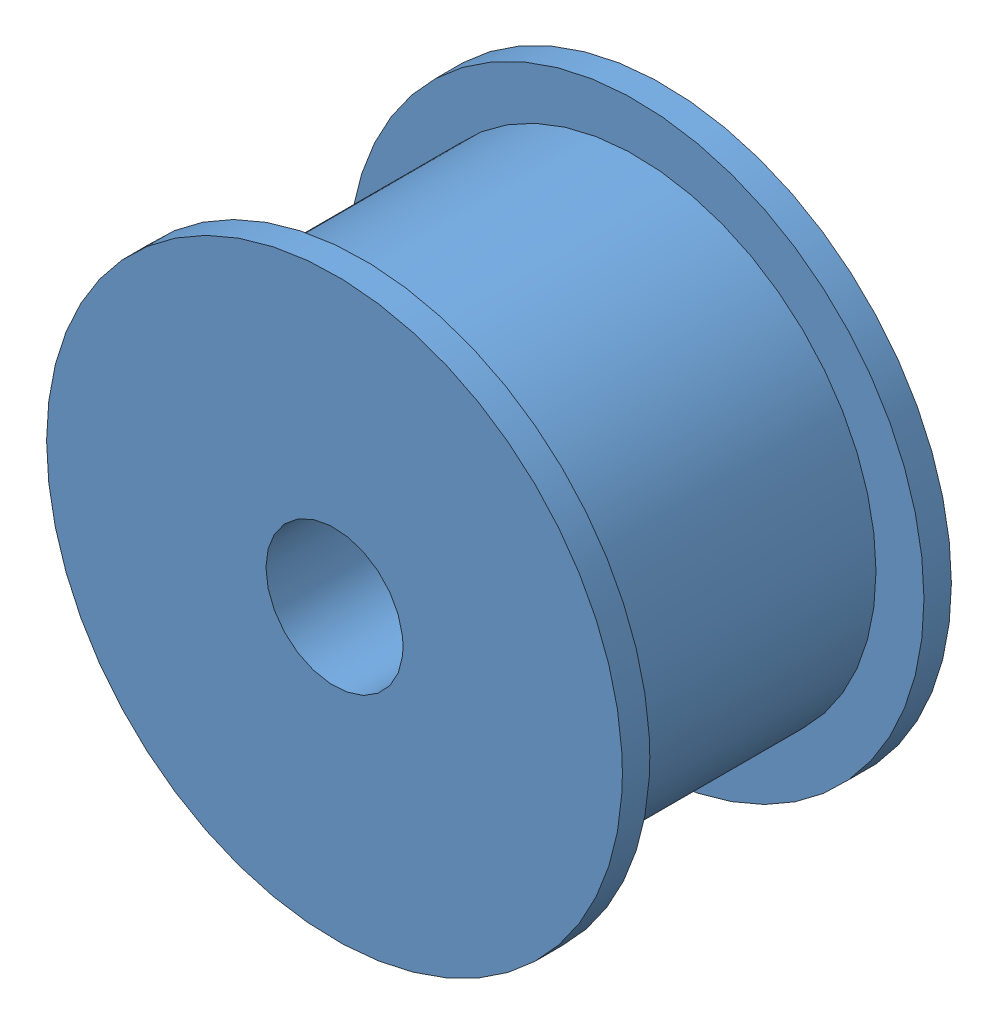
SolidWorks assembly Assemblage Poulie Lisse BRS, configuration Défaut. Lengths in mm.
Overall size (21 21 12).
6 component instances, 5 part files, 10 mates.
Components (placement in the parent):
- Poulie Lisse D5 BRP-1: Poulie Lisse D5 BRP [Défaut] at (3.2049 -2.4927 26) size (21 21 12)
- Vis Poulie Lisse L40 D5 BRS-1: Vis Poulie Lisse L40 D5 BRS [Défaut] at (3.2049 -2.4927 13) x (0.898963 0.438024 0) z (0 0 1) (suppressed, hidden)
- Rondelle M5 BRS-1: Rondelle M5 BRS [Défaut] at (3.2049 -2.4927 39.7) x (0.999434 0.033648 0) z (0 0 1) (suppressed, hidden)
- Rondelle M5 BRS-2: Rondelle M5 BRS [Défaut] at (3.2049 -2.4927 31) (suppressed, hidden)
- Bague lisse D5 L4 BRS-1: Bague lisse D5 L4 BRS [Défaut] at (3.2049 -2.4927 27) (suppressed, hidden)
- Ecrou M5 BRS-1: Ecrou M5 BRS [Défaut] at (3.2049 -2.4927 40.4) (suppressed, hidden)
Mates (geometry in assembly coordinates):
- Coaxiale1: concentric aligned: cylinder of Poulie Lisse D5 BRP-1 through (3.2049 -2.4927 27) axis (0 0 -1) radius 2.5; cylinder of Vis Poulie Lisse L40 D5 BRS-1 through (3.2049 -2.4927 48) axis (0 0 -1) radius 2.5
- Coïncidente1: coincident anti-aligned: plane of Poulie Lisse D5 BRP-1 through (3.2049 -2.4927 15) normal (0 0 -1); plane of Vis Poulie Lisse L40 D5 BRS-1 through (3.2049 -2.4927 15) normal (0 0 1)
- Coaxiale2: concentric aligned: cylinder of Vis Poulie Lisse L40 D5 BRS-1 through (3.2049 -2.4927 48) axis (0 0 -1) radius 2.5; cylinder of Bague lisse D5 L4 BRS-1 through (3.2049 -2.4927 31) axis (0 0 -1) radius 2.5
- Coïncidente2: coincident anti-aligned: plane of Poulie Lisse D5 BRP-1 through (3.2049 -2.4927 27) normal (0 0 1); plane of Bague lisse D5 L4 BRS-1 through (3.2049 -2.4927 27) normal (0 0 -1)
- Coaxiale3: concentric anti-aligned: cylinder of Vis Poulie Lisse L40 D5 BRS-1 through (3.2049 -2.4927 48) axis (0 0 -1) radius 2.5; cylinder of Rondelle M5 BRS-2 through (3.2049 -2.4927 30.2) axis (0 0 1) radius 2.5
- Coïncidente3: coincident anti-aligned: plane of Rondelle M5 BRS-2 through (3.2049 -2.4927 31) normal (0 0 -1); plane of Bague lisse D5 L4 BRS-1 through (3.2049 -2.4927 31) normal (0 0 1)
- Coaxiale4: concentric anti-aligned: cylinder of Vis Poulie Lisse L40 D5 BRS-1 through (3.2049 -2.4927 48) axis (0 0 -1) radius 2.5; cylinder of Rondelle M5 BRS-1 through (3.2049 -2.4927 38.9) axis (0 0 1) radius 2.5
- Coaxiale5: concentric aligned: cylinder of Vis Poulie Lisse L40 D5 BRS-1 through (3.2049 -2.4927 48) axis (0 0 -1) radius 2.5; cylinder of Ecrou M5 BRS-1 through (3.2049 -2.4927 44.4) axis (0 0 -1) radius 2.5
- Coïncidente4: coincident anti-aligned: plane of Rondelle M5 BRS-1 through (3.2049 -2.4927 40.4) normal (0 0 1); plane of Ecrou M5 BRS-1 through (3.2049 -2.4927 40.4) normal (0 0 -1)
- Distance1: distance = 8 mm anti-aligned: plane of Rondelle M5 BRS-1 through (3.2049 -2.4927 39.7) normal (0 0 -1); plane of Rondelle M5 BRS-2 through (3.2049 -2.4927 31.7) normal (0 0 1)
